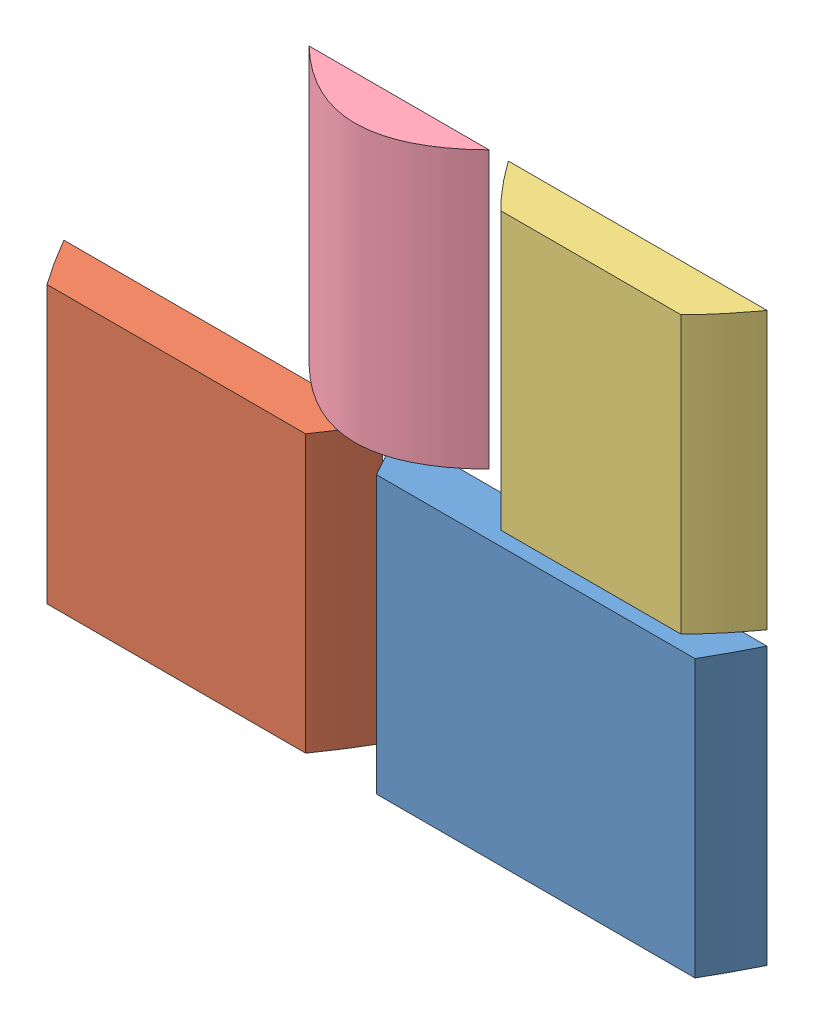
SolidWorks assembly Assem2, configuration Default. Lengths in mm.
Overall size (762.62 615.37 50.8).
4 component instances, 4 part files, 6 mates.
Components (placement in the parent):
- cut_1-1: cut_1 [Default] at (176.9388 81.7014 378.7639) size (400 300 50.8)
- cut_2-1: cut_2 [Default] at (-212.9395 81.7014 327.9639) size (345.49 300 50.8)
- cut_3-1: cut_3 [Default] at (236.6533 397.0721 277.1639) size (280.57 300 50.8)
- cut_4-1: cut_4 [Default] at (-22.1386 397.0721 226.3639) size (195.14 300 47.6)
Mates (geometry in assembly coordinates):
- Coincident1: coincident aligned: plane of cut_1-1 through (-23.0612 381.7014 378.7639) normal (0 0 -1); plane of cut_2-1 through (-435.6163 31.7014 378.7639) normal (0 0 -1)
- Coincident2: coincident aligned: plane of cut_2-1 through (-435.6163 31.7014 378.7639) normal (0 0 -1); plane of cut_3-1 through (-5.3478 347.0721 378.7639) normal (0 0 -1)
- Coincident3: coincident aligned: plane of cut_3-1 through (-5.3478 347.0721 378.7639) normal (0 0 -1); plane of cut_4-1 through (-264.5833 347.0721 378.7639) normal (0 0 -1)
- Coincident4: coincident aligned: line of cut_1-1 through (376.9388 81.7014 378.7639) axis (-1 0 0); line of cut_2-1 through (-40.197 81.7014 378.7639) axis (-1 0 0)
- Coincident5: coincident anti-aligned: line of cut_1-1 through (376.9388 381.7014 378.7639) axis (0 -1 0); line of cut_3-1 through (376.9388 397.0721 378.7639) axis (0 1 0)
- Coincident6: coincident aligned: line of cut_3-1 through (376.9388 397.0721 378.7639) axis (-1 0 0); line of cut_4-1 through (75.4319 397.0721 378.7639) axis (-1 0 0)
